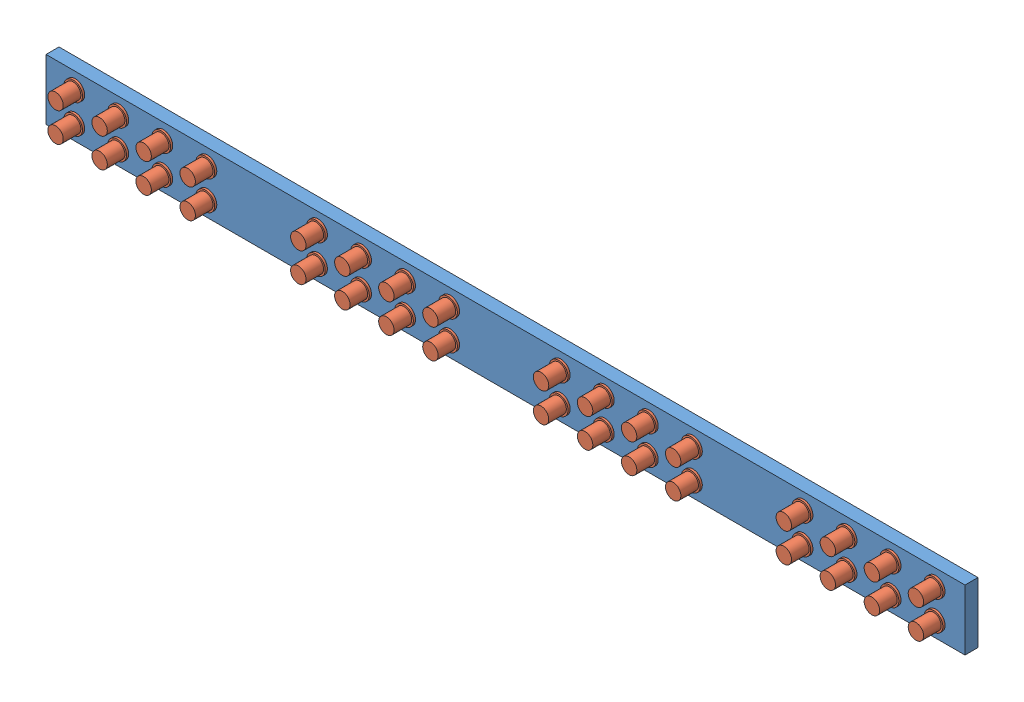
SolidWorks assembly pogo-plate, configuration Default. Lengths in mm.
Overall size (106 7 5.21).
33 component instances, 2 part files, 6 mates.
Components (placement in the parent):
- pogo-plate-1: pogo-plate [Default] at origin size (106 7 1.5)
- pogo-pin.millmax-0926-1-1: pogo-pin.millmax-0926-1 [Default] at (-49.62 1.6837 1.75) size (2.16 2.16 5.21)
- pogo-pin.millmax-0926-1-2: pogo-pin.millmax-0926-1 [Default] at (-49.62 -1.6837 1.75) x (0.230919 -0.972973 0) z (0 0 1) size (2.16 2.16 5.21)
- pogo-pin.millmax-0926-1-3: pogo-pin.millmax-0926-1 [Default] at (-44.54 -1.6837 1.75) x (0.230919 -0.972973 0) z (0 0 1) size (2.16 2.16 5.21)
- pogo-pin.millmax-0926-1-4: pogo-pin.millmax-0926-1 [Default] at (-39.46 -1.6837 1.75) x (0.230919 -0.972973 0) z (0 0 1) size (2.16 2.16 5.21)
- pogo-pin.millmax-0926-1-5: pogo-pin.millmax-0926-1 [Default] at (-34.38 -1.6837 1.75) x (0.230919 -0.972973 0) z (0 0 1) size (2.16 2.16 5.21)
- pogo-pin.millmax-0926-1-6: pogo-pin.millmax-0926-1 [Default] at (-44.54 1.6837 1.75) size (2.16 2.16 5.21)
- pogo-pin.millmax-0926-1-7: pogo-pin.millmax-0926-1 [Default] at (-39.46 1.6837 1.75) size (2.16 2.16 5.21)
- pogo-pin.millmax-0926-1-8: pogo-pin.millmax-0926-1 [Default] at (-34.38 1.6837 1.75) size (2.16 2.16 5.21)
- pogo-pin.millmax-0926-1-9: pogo-pin.millmax-0926-1 [Default] at (-11.46 1.6837 1.75) size (2.16 2.16 5.21)
- pogo-pin.millmax-0926-1-10: pogo-pin.millmax-0926-1 [Default] at (16.54 1.6837 1.75) size (2.16 2.16 5.21)
- pogo-pin.millmax-0926-1-11: pogo-pin.millmax-0926-1 [Default] at (44.54 1.6837 1.75) size (2.16 2.16 5.21)
- pogo-pin.millmax-0926-1-12: pogo-pin.millmax-0926-1 [Default] at (-16.54 -1.6837 1.75) x (0.230919 -0.972973 0) z (0 0 1) size (2.16 2.16 5.21)
- pogo-pin.millmax-0926-1-13: pogo-pin.millmax-0926-1 [Default] at (11.46 -1.6837 1.75) x (0.230919 -0.972973 0) z (0 0 1) size (2.16 2.16 5.21)
- pogo-pin.millmax-0926-1-14: pogo-pin.millmax-0926-1 [Default] at (39.46 -1.6837 1.75) x (0.230919 -0.972973 0) z (0 0 1) size (2.16 2.16 5.21)
- pogo-pin.millmax-0926-1-15: pogo-pin.millmax-0926-1 [Default] at (-6.38 -1.6837 1.75) x (0.230919 -0.972973 0) z (0 0 1) size (2.16 2.16 5.21)
- pogo-pin.millmax-0926-1-16: pogo-pin.millmax-0926-1 [Default] at (21.62 -1.6837 1.75) x (0.230919 -0.972973 0) z (0 0 1) size (2.16 2.16 5.21)
- pogo-pin.millmax-0926-1-17: pogo-pin.millmax-0926-1 [Default] at (49.62 -1.6837 1.75) x (0.230919 -0.972973 0) z (0 0 1) size (2.16 2.16 5.21)
- pogo-pin.millmax-0926-1-18: pogo-pin.millmax-0926-1 [Default] at (-6.38 1.6837 1.75) size (2.16 2.16 5.21)
- pogo-pin.millmax-0926-1-19: pogo-pin.millmax-0926-1 [Default] at (21.62 1.6837 1.75) size (2.16 2.16 5.21)
- pogo-pin.millmax-0926-1-20: pogo-pin.millmax-0926-1 [Default] at (49.62 1.6837 1.75) size (2.16 2.16 5.21)
- pogo-pin.millmax-0926-1-21: pogo-pin.millmax-0926-1 [Default] at (-21.62 -1.6837 1.75) x (0.230919 -0.972973 0) z (0 0 1) size (2.16 2.16 5.21)
- pogo-pin.millmax-0926-1-22: pogo-pin.millmax-0926-1 [Default] at (6.38 -1.6837 1.75) x (0.230919 -0.972973 0) z (0 0 1) size (2.16 2.16 5.21)
- pogo-pin.millmax-0926-1-23: pogo-pin.millmax-0926-1 [Default] at (34.38 -1.6837 1.75) x (0.230919 -0.972973 0) z (0 0 1) size (2.16 2.16 5.21)
- pogo-pin.millmax-0926-1-24: pogo-pin.millmax-0926-1 [Default] at (-11.46 -1.6837 1.75) x (0.230919 -0.972973 0) z (0 0 1) size (2.16 2.16 5.21)
- pogo-pin.millmax-0926-1-25: pogo-pin.millmax-0926-1 [Default] at (16.54 -1.6837 1.75) x (0.230919 -0.972973 0) z (0 0 1) size (2.16 2.16 5.21)
- pogo-pin.millmax-0926-1-26: pogo-pin.millmax-0926-1 [Default] at (44.54 -1.6837 1.75) x (0.230919 -0.972973 0) z (0 0 1) size (2.16 2.16 5.21)
- pogo-pin.millmax-0926-1-27: pogo-pin.millmax-0926-1 [Default] at (-16.54 1.6837 1.75) size (2.16 2.16 5.21)
- pogo-pin.millmax-0926-1-28: pogo-pin.millmax-0926-1 [Default] at (11.46 1.6837 1.75) size (2.16 2.16 5.21)
- pogo-pin.millmax-0926-1-29: pogo-pin.millmax-0926-1 [Default] at (39.46 1.6837 1.75) size (2.16 2.16 5.21)
- pogo-pin.millmax-0926-1-30: pogo-pin.millmax-0926-1 [Default] at (-21.62 1.6837 1.75) size (2.16 2.16 5.21)
- pogo-pin.millmax-0926-1-31: pogo-pin.millmax-0926-1 [Default] at (6.38 1.6837 1.75) size (2.16 2.16 5.21)
- pogo-pin.millmax-0926-1-32: pogo-pin.millmax-0926-1 [Default] at (34.38 1.6837 1.75) size (2.16 2.16 5.21)
Mates (geometry in assembly coordinates):
- Tangent1: tangent anti-aligned: cylinder of pogo-pin.millmax-0926-1-1 through (-49.62 1.6837 3.78) axis (0 0 -1) radius 0.89; plane of assembly through (0 0.7937 0) normal (0 1 0)
- Tangent2: tangent aligned: cylinder of pogo-pin.millmax-0926-1-2 through (-49.62 -1.6837 3.78) axis (0 0 -1) radius 0.89; plane of assembly through (0 -0.7937 0) normal (0 1 0)
- Tangent3: tangent aligned: cylinder of pogo-pin.millmax-0926-1-1 through (-49.62 1.6837 3.78) axis (0 0 -1) radius 0.89; plane of assembly through (-48.73 0 0) normal (1 0 0)
- Tangent4: tangent aligned: cylinder of pogo-pin.millmax-0926-1-2 through (-49.62 -1.6837 3.78) axis (0 0 -1) radius 0.89; plane of assembly through (-48.73 0 0) normal (1 0 0)
- Coincident1: coincident anti-aligned: plane of pogo-plate-1 through (0 0 1.5) normal (0 0 1); plane of pogo-pin.millmax-0926-1-1 through (-49.62 1.6837 1.5) normal (0 0 -1)
- Coincident2: coincident anti-aligned: plane of pogo-plate-1 through (0 0 1.5) normal (0 0 1); plane of pogo-pin.millmax-0926-1-2 through (-49.62 -1.6837 1.5) normal (0 0 -1)
